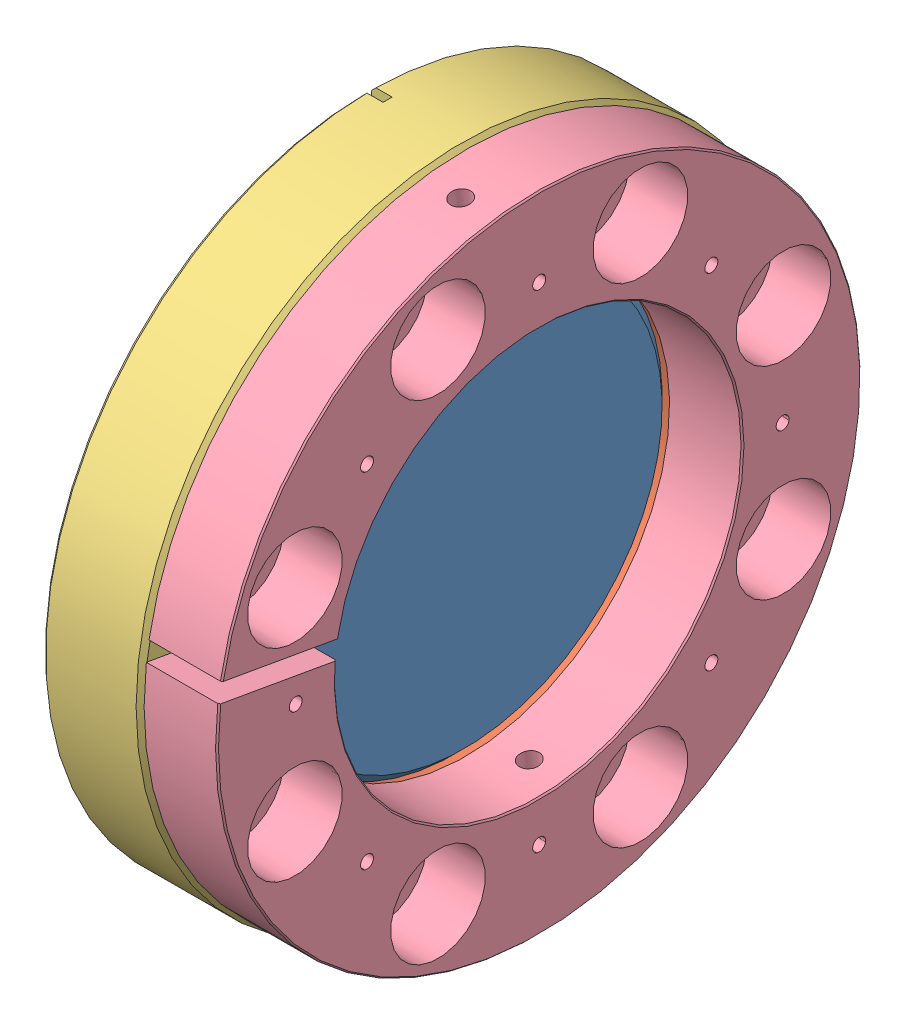
SolidWorks assembly 4.5 VP Assembly, configuration Default. Lengths in mm.
Overall size (29.97 146.69 146.69).
6 component instances, 4 part files, 3 mates.
Components (placement in the parent):
- Viewport 4.5_9722007-1: Viewport 4.5_9722007 [Default] at (9.7649 66.3669 94.969) size (17.27 113.54 113.54)
  - 1004602A-1: 1004602A [Default] at (1.2954 0 0) x (0 1 0) z (-1 0 0) size (73.79 73.79 15.62)
    - 1002203A-1: 1002203A [Default] at (0 0 -9.271) x (-1 0 0) z (0 0 -1) size (72.01 72.01 6.35)
    - Viewport 4.5 P1_0194302B-1: Viewport 4.5 P1_0194302B [Default] at origin size (73.79 73.79 15.49)
  - Viewport 4.5 P2_0194603B-1: Viewport 4.5 P2_0194603B [Default] at origin size (17.27 113.54 113.54)
- Viewport Washer 4.5-1: Viewport Washer 4.5 [Default] at (27.0369 66.3669 94.969) x (0 0.382683 -0.92388) z (1 0 0) size (112.27 112.27 12.7)
Mates (geometry in assembly coordinates):
- Coincident1: coincident anti-aligned: plane of Viewport 4.5_9722007-1/Viewport 4.5 P2_0194603B-1 through (27.0369 66.3669 94.969) normal (1 0 0); plane of Viewport Washer 4.5-1 through (27.0369 66.3669 94.969) normal (-1 0 0)
- Concentric1: concentric anti-aligned: circle of Viewport 4.5_9722007-1/1004602A-1/Viewport 4.5 P1_0194302B-1; circle of Viewport Washer 4.5-1
- Coincident2: coincident anti-aligned: cylinder of Viewport 4.5_9722007-1/Viewport 4.5 P2_0194603B-1 through (27.0369 108.9352 112.6014) axis (-1 0 0) radius 4.2164; circle of Viewport Washer 4.5-1
